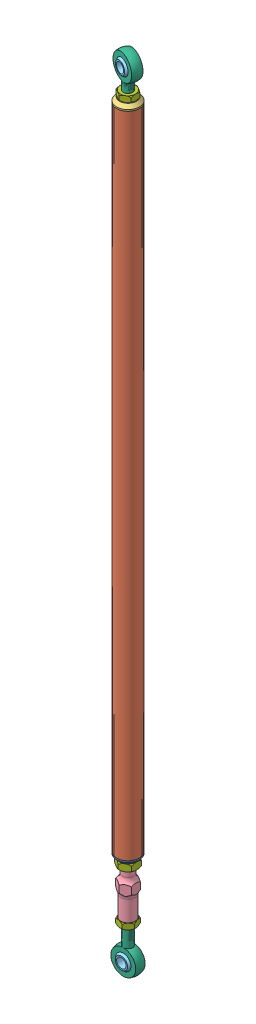
SolidWorks assembly PushRodRear, configuration Default. Lengths in mm.
Overall size (111.88 670.22 26.65).
13 component instances, 7 part files, 20 mates.
Components (placement in the parent):
- ControlArmEnd75-375-4: ControlArmEnd75-375 [Default] at (0 -525.3274 0) x (0.999824 0 0.018739) z (-0.018739 0 0.999824) size (19.05 7 19.05)
- PushRodTubeRear-1: PushRodTubeRear [No Fairing] at origin size (111.88 543 22.33)
- ControlArmEnd75-312-3: ControlArmEnd75-312 [Default] at (0 25.6726 0) x (-0.96098 0 -0.276617) z (-0.276617 0 0.96098) size (19.05 7 19.05)
- RodEndAdjuster312-1: RodEndAdjuster312 [Default] at (0 -542.7274 0) x (-0.490119 0 0.871655) z (-0.871655 0 -0.490119) size (13 57.4 16.97)
- RodEnd312Male-2: RodEnd312Male [Default] at (0 48.6726 0) x (0.974096 0 0.226134) z (-0.226134 0 0.974096) size (22.23 58.75 22.2)
  - RodEndBall312-1: RodEndBall312 [Default] at origin size (15.06 15.06 22.2)
  - RodEndRace312Male-1: RodEndRace312Male [Default] at origin size (22.23 58.75 7.94)
- RodEnd312Male-1: RodEnd312Male [Default] at (0 -599.3274 0) x (-0.999997 0 0.002341) z (0.002341 0 0.999997) size (22.23 58.75 22.2)
  - RodEndBall312-1: RodEndBall312 [Default] at origin size (15.06 15.06 22.2)
  - RodEndRace312Male-1: RodEndRace312Male [Default] at origin size (22.23 58.75 7.94)
- Hex Jam Nut_AI-1: Hex Jam Nut_AI [HJNUT 0.3125-24-D-N] at (0 -573.6804 0) x (0.723024 0 0.690823) z (0 -1 0) size (12.7 14.66 4.95)
- Hex Jam Nut_AI-2: Hex Jam Nut_AI [HJNUT 0.3125-24-D-N] at (0 25.6726 0) x (1 0 0) z (0 -1 0) size (12.7 14.66 4.95)
- Hex Jam Nut_AI-3: Hex Jam Nut_AI [HJNUT 0.3750-24-D-N] at (0 -531.0932 0) x (1 0 0) z (0 -1 0) size (14.27 16.48 5.77)
Mates (geometry in assembly coordinates):
- Concentric7: concentric: cylinder of assembly; cylinder of assembly; cylinder of ControlArmEnd75-375-4 through (0 -521.3274 0) axis (0 1 0) radius 7.925; cylinder of PushRodTubeRear-1 through (0 21.6726 0) axis (0 -1 0) radius 8.325
- Coincident2026: coincident: plane of assembly; plane of assembly; plane of ControlArmEnd75-375-4 through (0 -521.3274 0) normal (0 1 0); plane of PushRodTubeRear-1 through (0 -521.3274 0) normal (0 -1 0)
- Coincident2022: coincident: plane of assembly through (0 0 0) normal (0 1 0); plane of PushRodTubeRear-1 through (0 0 0) normal (0 1 0); plane of assembly
- Coincident2023: coincident: plane of assembly through (0 0 0) normal (0 0 1); plane of PushRodTubeRear-1 through (0 0 0) normal (0 0 1); plane of assembly
- Coincident2024: coincident: plane of assembly through (0 0 0) normal (1 0 0); plane of PushRodTubeRear-1 through (0 0 0) normal (1 0 0); plane of assembly
- Concentric8: concentric: cylinder of assembly; cylinder of assembly; cylinder of PushRodTubeRear-1 through (0 21.6726 0) axis (0 -1 0) radius 9.525; cylinder of ControlArmEnd75-312-3 through (0 18.6726 0) axis (0 1 0) radius 9.525
- Coincident2025: coincident: plane of assembly; plane of assembly; plane of PushRodTubeRear-1 through (0 21.6726 0) normal (0 1 0); plane of ControlArmEnd75-312-3 through (0 21.6726 0) normal (0 -1 0)
- Concentric12: concentric: cylinder of assembly; cylinder of assembly; cylinder of PushRodTubeRear-1 through (0 21.6726 0) axis (0 -1 0) radius 9.525; cylinder of RodEndAdjuster312-1 through (0 -511.3274 0) axis (0 -1 0) radius 4.7625
- Distance2: distance = 14 mm: plane of assembly; plane of assembly; plane of ControlArmEnd75-375-4 through (0 -525.3274 0) normal (0 -1 0); plane of RodEndAdjuster312-1 through (0 -511.3274 0) normal (0 1 0)
- Distance3: distance = 23 mm: plane of ? through (0 48.6726 0) normal (0 1 0); plane of ControlArmEnd75-312-3 through (0 25.6726 0) normal (0 1 0)
- Concentric102: concentric: cylinder of assembly; cylinder of assembly; cylinder of RodEndAdjuster312-1 through (0 -511.3274 0) axis (0 1 0) radius 4.7625; cylinder of PushRodTubeRear-1 through (0 21.6726 0) axis (0 -1 0) radius 9.525
- Concentric103: concentric: line of PushRodTubeRear-1 through (468 0 -521.3274) axis (0 0 1); cylinder of ? through (0 40.5601 0) axis (0 -1 0) radius 3.9688
- Distance4: distance = 648 mm: point of RodEnd312Male-2/RodEndBall312-1; point of RodEnd312Male-1/RodEndBall312-1
- Concentric105: concentric: cylinder of RodEndAdjuster312-1 through (0 -568.7274 0) axis (0 1 0) radius 6; cylinder of ? through (0 -591.2149 0) axis (0 1 0) radius 3.9688
- Concentric106: concentric: cylinder of ? through (0 40.5601 0) axis (0 -1 0) radius 3.9688; cylinder of Hex Jam Nut_AI-2 through (0 30.6256 0) axis (0 -1 0) radius 3.4544
- Coincident2027: coincident: plane of assembly; plane of assembly; plane of ControlArmEnd75-312-3 through (0 25.6726 0) normal (0 1 0); plane of Hex Jam Nut_AI-2 through (0 25.6726 7.3323) normal (0 -1 0)
- Concentric107: concentric: cylinder of ? through (0 -591.2149 0) axis (0 1 0) radius 3.9688; cylinder of Hex Jam Nut_AI-1 through (0 -568.7274 0) axis (0 -1 0) radius 3.4544
- Coincident2028: coincident: plane of assembly; plane of assembly; plane of RodEndAdjuster312-1 through (0 -568.7274 0) normal (0 -1 0); plane of Hex Jam Nut_AI-1 through (-5.0654 -568.7274 5.3015) normal (0 1 0)
- Concentric108: concentric: cylinder of assembly; cylinder of assembly; cylinder of RodEndAdjuster312-1 through (0 -511.3274 0) axis (0 -1 0) radius 4.7625; cylinder of Hex Jam Nut_AI-3 through (0 -525.3274 0) axis (0 -1 0) radius 4.2164
- Coincident2029: coincident: plane of assembly; plane of assembly; plane of ControlArmEnd75-375-4 through (0 -525.3274 0) normal (0 -1 0); plane of Hex Jam Nut_AI-3 through (-14.2748 -525.3274 0) normal (0 1 0)
